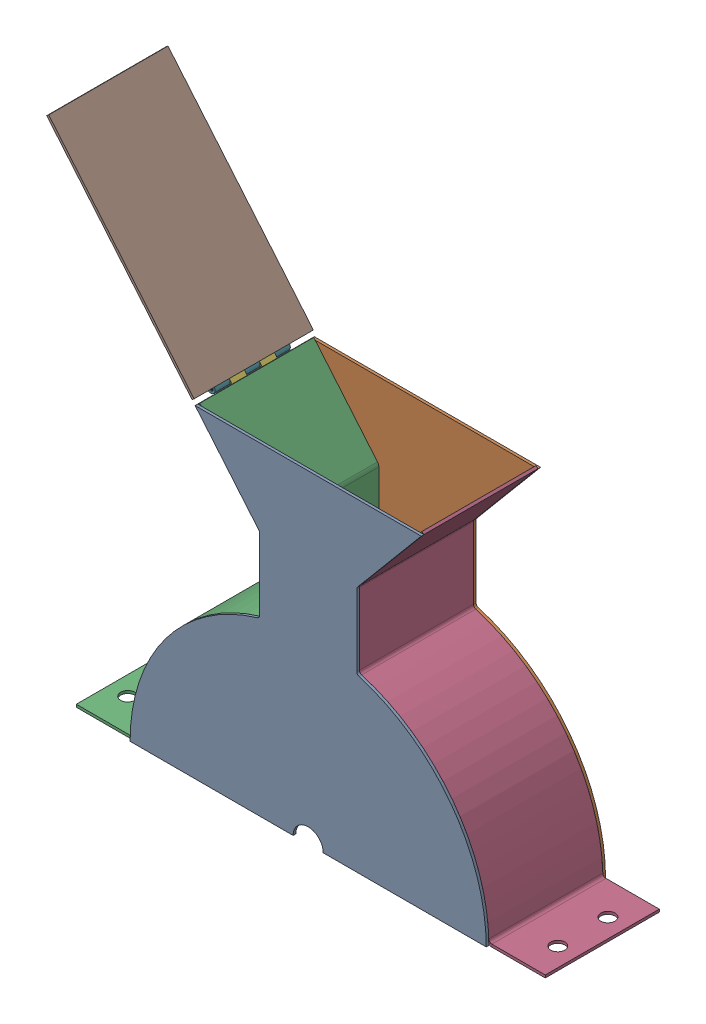
SolidWorks assembly Upper Crushing Chamber Assembly, configuration Default. Lengths in mm.
Overall size (502.58 508.58 120.88).
6 component instances, 4 part files, 14 mates.
Components (placement in the parent):
- Outer Casing - Upper Flat-1: Outer Casing - Upper Flat [Default] at (130.0519 28.1852 388.305) size (360.91 327.62 2.66)
- Outer Casing - Upper Flat-2: Outer Casing - Upper Flat [Default] at (130.0519 28.1852 270.0782) size (360.91 327.62 2.66)
- Outer Casing - Upper Curved-1: Outer Casing - Upper Curved [Default] at (130.0519 28.1852 270.0782) x (1 -0.000027 0) z (0 0 1) size (190.98 329.36 115.57)
- Outer Casing - Upper Curved-2: Outer Casing - Upper Curved [Default] at (130.0519 28.1852 385.6482) x (-1 -0.000027 0) z (0 0 -1) size (190.98 329.36 115.57)
- Hinger-1: Hinger [16175A61] at (9.0629 356.6572 327.8632) x (-0.642788 0.766044 0) z (0 0 1) size (50.8 8.73 77.91)
- Funnel Cover-1: Funnel Cover [Default] at (12.4071 359.4634 388.305) x (-0.642788 0.766044 0) z (-0.766044 -0.642788 0) size (229.2 120.88 2.66)
Mates (geometry in assembly coordinates):
- Coincident1: coincident aligned: circle of Upper Assembly - Front Face no flange-1; circle of Upper Assembly - Side Piece 2.0-1
- Parallel1: parallel anti-aligned: line of Upper Assembly - Front Face no flange-1 through (80.7606 276.824 385.6482) axis (0 -1 0); line of Upper Assembly - Side Piece 2.0-1 through (80.7654 204.1637 385.6482) axis (0 1 0)
- Coincident3: coincident anti-aligned: circle of Upper Assembly - Front Face no flange-1; circle of Upper Assembly - Side Piece 2.0-2
- Parallel2: parallel anti-aligned: line of Upper Assembly - Front Face no flange-1 through (179.3431 204.1623 385.6482) axis (0 1 0); line of Upper Assembly - Side Piece 2.0-2 through (176.6815 276.8415 385.6482) axis (0 -1 0)
- Coincident13: coincident aligned: circle of Upper Assembly - Front Face no flange-2; circle of Upper Assembly - Side Piece 2.0-1
- Parallel6: parallel aligned: line of Upper Assembly - Front Face no flange-2 through (179.3431 204.1623 270.0782) axis (0 1 0); line of Upper Assembly - Side Piece 2.0-2 through (179.3384 204.1637 270.0782) axis (0 1 0)
- Coincident15: coincident anti-aligned: plane of Upper Assembly - Side Piece 2.0-1 through (224.1378 107.1326 270.0782) normal (-0.766044 -0.642788 0); plane of Upper Assembly - Hinge-1 through (28.7339 340.0058 365.9632) normal (0.766044 0.642788 0)
- Parallel7: parallel aligned: line of Upper Assembly - Side Piece 2.0-1 through (80.0226 278.8824 385.6482) axis (0 0 -1); line of Upper Assembly - Hinge-1 through (27.2746 338.7813 365.9632) axis (0 0 -1)
- Coincident17: coincident anti-aligned: line of Upper Assembly - Side Piece 2.0-1 through (15.4582 355.8273 270.0782) axis (0 0 1); line of Upper Assembly - Hinge-1 through (15.4582 355.8273 365.9632) axis (0 0 -1)
- Coincident18: coincident: plane of assembly; point of Outer Casing - Upper Curved-1; plane of Hinger-1 through (28.7339 340.0058 365.9632) normal (0 0 1)
- Coincident19: coincident anti-aligned: plane of Upper Assembly - Hinge-1 through (-3.9197 378.9209 365.9632) normal (0.766044 0.642788 0); plane of Upper Assembly - Funnel Cover-1 through (12.4071 359.4634 388.305) normal (-0.766044 -0.642788 0)
- Parallel8: parallel aligned: line of Upper Assembly - Hinge-1 through (-3.9197 378.9209 365.9632) axis (0 0 -1); line of Upper Assembly - Funnel Cover-1 through (12.4071 359.4634 365.9632) axis (0 0 -1)
- Coincident21: coincident aligned: line of Upper Assembly - Funnel Cover-1 through (12.4071 359.4634 365.9632) axis (0 0 -1); line of Upper Assembly - Hinge-1 through (12.4071 359.4634 335.4832) axis (0 0 -1)
- Coincident22: coincident: line of Upper Assembly - Hinge-1 through (12.4071 359.4634 365.9632) axis (-0.642788 0.766044 0)
